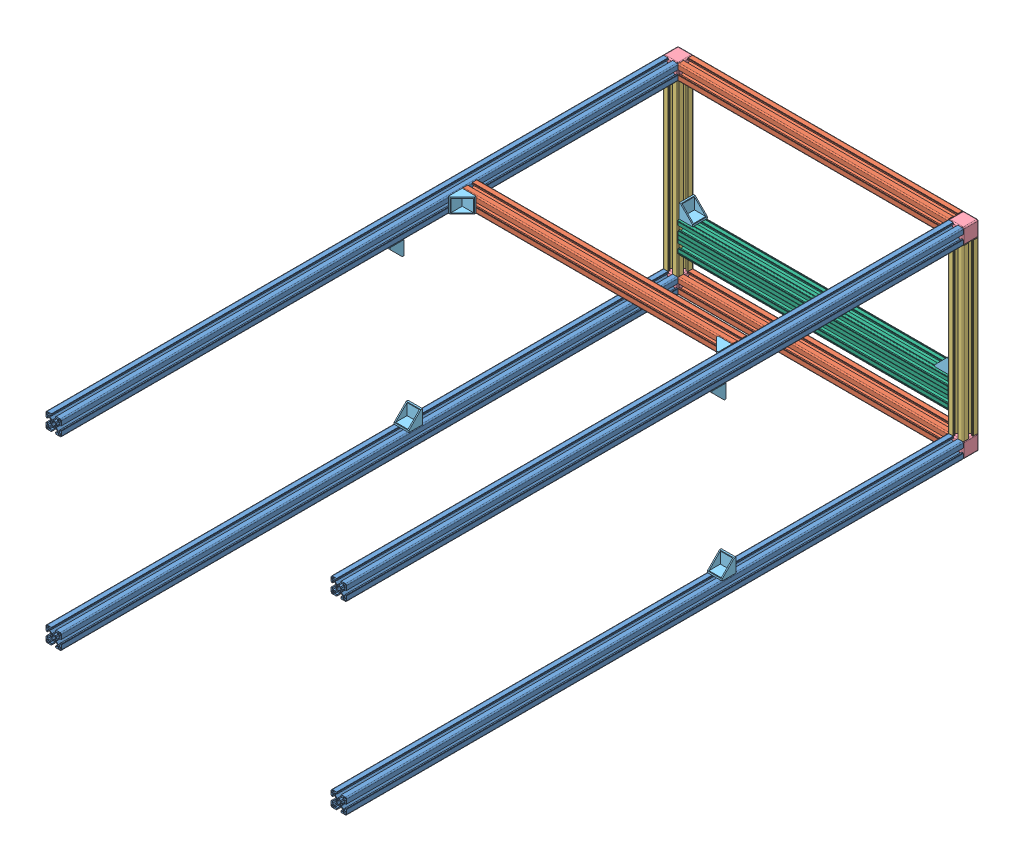
SolidWorks assembly bati partie haute, configuration Défaut. Lengths in mm.
Overall size (780 520 1640).
22 component instances, 6 part files, 59 mates.
Components (placement in the parent):
- 1636 mm-1: 1636 mm [Défaut] at (-690.2499 -110.2045 843.4804) size (40 40 1600)
- 1636 mm-2: 1636 mm [Défaut] at (49.7501 -110.2045 843.4804) x (0 1 0) z (0 0 1) size (40 40 1600)
- 1636 mm-3: 1636 mm [Défaut] at (49.7501 369.7955 843.4804) x (0 -1 0) z (0 0 1) size (40 40 1600)
- 1636 mm-4: 1636 mm [Défaut] at (-690.2499 369.7955 843.4804) size (40 40 1600)
- 700 mm-1: 700 mm [Défaut] at (-570.2499 369.7955 -676.5196) x (0 0 1) z (-1 0 0) size (40 40 700)
- 700 mm-2: 700 mm [Défaut] at (-70.2499 -110.2045 -676.5196) x (0 0 -1) z (1 0 0) size (40 40 700)
- 440 mm-1: 440 mm [Défaut] at (49.7501 249.7955 -676.5196) x (1 0 0) z (0 1 0) size (40 40 440)
- 440 mm-2: 440 mm [Défaut] at (-690.2499 249.7955 -676.5196) x (1 0 0) z (0 1 0) size (40 40 440)
- cache 40 40 40-1: cache 40 40 40 [Défaut] at (-708.8962 368.9411 -656.5196) x (-1 0 0) z (0 0 -1) size (40 40 40)
- cache 40 40 40-2: cache 40 40 40 [Défaut] at (-671.6035 -109.35 -656.5196) x (1 0 0) z (0 0 -1) size (40 40 40)
- cache 40 40 40-3: cache 40 40 40 [Défaut] at (48.8957 388.4419 -656.5196) x (0 1 0) z (0 0 -1) size (40 40 40)
- cache 40 40 40-4: cache 40 40 40 [Défaut] at (68.3965 -109.35 -656.5196) x (1 0 0) z (0 0 -1) size (40 40 40)
- 700 mm-3: 700 mm [Défaut] at (-70.2499 369.7955 -116.5196) x (0 0 -1) z (1 0 0) size (40 40 700)
- equerre 40x40-1: equerre 40x40 [Défaut] at (-670.2499 370.7955 -96.5196) x (0 1 0) z (0 0 1) size (38 36 36)
- equerre 40x40-2: equerre 40x40 [Défaut] at (-689.2499 -90.2045 6.1959) x (1 0 0) z (0 1 0) size (38 36 36)
- equerre 40x40-3: equerre 40x40 [Défaut] at (50.7501 349.7955 -40.9632) size (38 36 36)
- equerre 40x40-4: equerre 40x40 [Défaut] at (29.7501 39.7955 -677.5196) x (0 0 -1) z (-1 0 0) size (38 36 36)
- equerre 40x40-5: equerre 40x40 [Défaut] at (-689.2499 349.7955 54.8144) size (38 36 36)
- equerre 40x40-6: equerre 40x40 [Défaut] at (-670.2499 39.7955 -677.5196) x (0 0 1) z (1 0 0) size (38 36 36)
- equerre 40x40-7: equerre 40x40 [Défaut] at (29.7501 370.7955 -96.5196) x (0 -1 0) z (0 0 1) size (38 36 36)
- equerre 40x40-8: equerre 40x40 [Défaut] at (50.7501 -90.2045 -66.692) x (-1 0 0) z (0 0 1) size (38 36 36)
- 700-1: 700 [Défaut] at (-570.2499 -0.2045 -676.5196) x (0 0 1) z (-1 0 0) size (40 80 700)
Mates (geometry in assembly coordinates):
- Coïncidente5: coincident anti-aligned: plane of 1636 mm-4 through (-673.2499 352.7955 -656.5196) normal (0 0 -1); plane of cache 40 40 40-1 through (-670.2499 349.7955 -656.5196) normal (0 0 1)
- Coïncidente6: coincident aligned: plane of 1636 mm-4 through (-673.2499 389.7955 -656.5196) normal (0 1 0); plane of cache 40 40 40-1 through (-670.2499 389.7955 -696.5196) normal (0 1 0)
- Coïncidente7: coincident aligned: plane of 1636 mm-4 through (-670.2499 375.7955 -656.5196) normal (1 0 0); plane of cache 40 40 40-1 through (-670.2499 389.7955 -696.5196) normal (1 0 0)
- Coïncidente10: coincident anti-aligned: plane of 1636 mm-3 through (32.7501 352.7955 -656.5196) normal (0 0 -1); plane of cache 40 40 40-3 through (29.7501 349.7955 -656.5196) normal (0 0 1)
- Coïncidente11: coincident aligned: plane of 1636 mm-3 through (32.7501 349.7955 -656.5196) normal (0 -1 0); plane of cache 40 40 40-3 through (69.7501 349.7955 -696.5196) normal (0 -1 0)
- Coïncidente12: coincident aligned: plane of 1636 mm-3 through (69.7501 352.7955 -656.5196) normal (1 0 0); plane of cache 40 40 40-3 through (69.7501 349.7955 -696.5196) normal (1 0 0)
- Coïncidente13: coincident anti-aligned: plane of 1636 mm-2 through (66.7501 -93.2045 -656.5196) normal (0 0 -1); plane of cache 40 40 40-4 through (29.7501 -90.2045 -656.5196) normal (0 0 1)
- Coïncidente14: coincident aligned: plane of 1636 mm-2 through (32.7501 -130.2045 -656.5196) normal (0 -1 0); plane of cache 40 40 40-4 through (29.7501 -130.2045 -696.5196) normal (0 -1 0)
- Coïncidente15: coincident aligned: plane of 1636 mm-2 through (29.7501 -93.2045 -656.5196) normal (-1 0 0); plane of cache 40 40 40-4 through (29.7501 -130.2045 -696.5196) normal (-1 0 0)
- Coïncidente16: coincident aligned: plane of 1636 mm-1 through (-670.2499 -127.2045 -656.5196) normal (1 0 0); plane of cache 40 40 40-2 through (-670.2499 -130.2045 -696.5196) normal (1 0 0)
- Coïncidente17: coincident anti-aligned: plane of 1636 mm-1 through (-673.2499 -127.2045 -656.5196) normal (0 0 -1); plane of cache 40 40 40-2 through (-710.2499 -90.2045 -656.5196) normal (0 0 1)
- Coïncidente18: coincident aligned: plane of 1636 mm-1 through (-673.2499 -90.2045 -656.5196) normal (0 1 0); plane of cache 40 40 40-2 through (-710.2499 -90.2045 -696.5196) normal (0 1 0)
- Coïncidente19: coincident anti-aligned: plane of 700 mm-2 through (-670.2499 -127.2045 -693.5196) normal (-1 0 0); plane of cache 40 40 40-2 through (-670.2499 -130.2045 -696.5196) normal (1 0 0)
- Coïncidente20: coincident aligned: plane of 700 mm-2 through (-670.2499 -90.2045 -693.5196) normal (0 1 0); plane of cache 40 40 40-2 through (-710.2499 -90.2045 -696.5196) normal (0 1 0)
- Coïncidente21: coincident aligned: plane of 700 mm-2 through (-670.2499 -127.2045 -696.5196) normal (0 0 -1); plane of cache 40 40 40-2 through (-710.2499 -90.2045 -696.5196) normal (0 0 -1)
- Coïncidente22: coincident anti-aligned: plane of 700 mm-2 through (29.7501 -127.2045 -693.5196) normal (1 0 0); plane of cache 40 40 40-4 through (29.7501 -130.2045 -696.5196) normal (-1 0 0)
- Coïncidente23: coincident aligned: plane of 700 mm-2 through (-670.2499 -127.2045 -696.5196) normal (0 0 -1); plane of cache 40 40 40-4 through (29.7501 -90.2045 -696.5196) normal (0 0 -1)
- Coïncidente24: coincident aligned: plane of 700 mm-2 through (-670.2499 -90.2045 -693.5196) normal (0 1 0); plane of cache 40 40 40-4 through (29.7501 -90.2045 -696.5196) normal (0 1 0)
- Coïncidente25: coincident anti-aligned: plane of 440 mm-1 through (66.7501 -90.2045 -659.5196) normal (0 -1 0); plane of cache 40 40 40-4 through (29.7501 -90.2045 -696.5196) normal (0 1 0)
- Coïncidente26: coincident aligned: plane of 440 mm-1 through (69.7501 -90.2045 -659.5196) normal (1 0 0); plane of cache 40 40 40-4 through (69.7501 -130.2045 -696.5196) normal (1 0 0)
- Coïncidente27: coincident aligned: plane of 440 mm-1 through (66.7501 -90.2045 -696.5196) normal (0 0 -1); plane of cache 40 40 40-4 through (29.7501 -90.2045 -696.5196) normal (0 0 -1)
- Coïncidente28: coincident anti-aligned: plane of 440 mm-1 through (66.7501 349.7955 -659.5196) normal (0 1 0); plane of cache 40 40 40-3 through (69.7501 349.7955 -696.5196) normal (0 -1 0)
- Coïncidente29: coincident aligned: plane of 440 mm-1 through (69.7501 -90.2045 -659.5196) normal (1 0 0); plane of cache 40 40 40-3 through (69.7501 349.7955 -696.5196) normal (1 0 0)
- Coïncidente30: coincident aligned: plane of 440 mm-1 through (43.7501 -90.2045 -696.5196) normal (0 0 -1); plane of cache 40 40 40-3 through (29.7501 349.7955 -696.5196) normal (0 0 -1)
- Coïncidente31: coincident anti-aligned: plane of 700 mm-1 through (29.7501 352.7955 -659.5196) normal (1 0 0); plane of cache 40 40 40-3 through (29.7501 349.7955 -696.5196) normal (-1 0 0)
- Coïncidente32: coincident aligned: plane of 700 mm-1 through (29.7501 389.7955 -682.5196) normal (0 1 0); plane of cache 40 40 40-3 through (69.7501 389.7955 -696.5196) normal (0 1 0)
- Coïncidente33: coincident aligned: plane of 700 mm-1 through (29.7501 363.7955 -696.5196) normal (0 0 -1); plane of cache 40 40 40-3 through (29.7501 349.7955 -696.5196) normal (0 0 -1)
- Coïncidente34: coincident anti-aligned: plane of 700 mm-1 through (-670.2499 352.7955 -659.5196) normal (-1 0 0); plane of cache 40 40 40-1 through (-670.2499 389.7955 -696.5196) normal (1 0 0)
- Coïncidente35: coincident aligned: plane of 700 mm-1 through (29.7501 389.7955 -682.5196) normal (0 1 0); plane of cache 40 40 40-1 through (-670.2499 389.7955 -696.5196) normal (0 1 0)
- Coïncidente36: coincident aligned: plane of 700 mm-1 through (29.7501 363.7955 -696.5196) normal (0 0 -1); plane of cache 40 40 40-1 through (-670.2499 349.7955 -696.5196) normal (0 0 -1)
- Coïncidente37: coincident anti-aligned: plane of 440 mm-2 through (-673.2499 -90.2045 -659.5196) normal (0 -1 0); plane of cache 40 40 40-2 through (-710.2499 -90.2045 -696.5196) normal (0 1 0)
- Coïncidente38: coincident aligned: plane of 440 mm-2 through (-696.2499 -90.2045 -696.5196) normal (0 0 -1); plane of cache 40 40 40-2 through (-710.2499 -90.2045 -696.5196) normal (0 0 -1)
- Coïncidente39: coincident aligned: plane of 440 mm-2 through (-710.2499 -90.2045 -693.5196) normal (-1 0 0); plane of cache 40 40 40-2 through (-710.2499 -130.2045 -696.5196) normal (-1 0 0)
- Coïncidente49: coincident anti-aligned: plane of 1636 mm-4 through (-670.2499 352.7955 -656.5196) normal (1 0 0); plane of 700 mm-3 through (-670.2499 352.7955 -133.5196) normal (-1 0 0)
- Coïncidente50: coincident aligned: plane of 1636 mm-4 through (-673.2499 389.7955 -656.5196) normal (0 1 0); plane of 700 mm-3 through (-670.2499 389.7955 -110.5196) normal (0 1 0)
- Distance6: distance = 520 mm anti-aligned: plane of 700 mm-3 through (-670.2499 375.7955 -136.5196) normal (0 0 -1); plane of 700 mm-1 through (29.7501 375.7955 -656.5196) normal (0 0 1)
- Coïncidente55: coincident anti-aligned: plane of 1636 mm-4 through (-670.2499 352.7955 -656.5196) normal (1 0 0); plane of equerre 40x40-1 through (-670.2499 351.7955 -96.5196) normal (-1 0 0)
- Coïncidente56: coincident aligned: plane of 1636 mm-4 through (-673.2499 389.7955 -656.5196) normal (0 1 0); plane of equerre 40x40-1 through (-634.2499 389.7955 -96.5196) normal (0 1 0)
- Coïncidente57: coincident anti-aligned: plane of 700 mm-3 through (-670.2499 386.7955 -96.5196) normal (0 0 1); plane of equerre 40x40-1 through (-634.2499 351.7955 -96.5196) normal (0 0 -1)
- Coïncidente58: coincident anti-aligned: plane of 1636 mm-4 through (-684.2499 349.7955 -656.5196) normal (0 -1 0); plane of equerre 40x40-5 through (-708.2499 349.7955 54.8144) normal (0 1 0)
- Coïncidente59: coincident aligned: plane of 1636 mm-4 through (-670.2499 352.7955 -656.5196) normal (1 0 0); plane of equerre 40x40-5 through (-670.2499 313.7955 54.8144) normal (1 0 0)
- Coïncidente61: coincident aligned: plane of 1636 mm-1 through (-670.2499 -104.2045 -656.5196) normal (1 0 0); plane of equerre 40x40-2 through (-670.2499 -90.2045 42.1959) normal (1 0 0)
- Coïncidente63: coincident anti-aligned: plane of 1636 mm-1 through (-696.2499 -90.2045 -656.5196) normal (0 1 0); plane of equerre 40x40-2 through (-708.2499 -90.2045 42.1959) normal (0 -1 0)
- Coïncidente64: coincident anti-aligned: plane of 1636 mm-3 through (55.7501 349.7955 -656.5196) normal (0 -1 0); plane of equerre 40x40-3 through (31.7501 349.7955 -40.9632) normal (0 1 0)
- Coïncidente65: coincident aligned: plane of 1636 mm-3 through (69.7501 352.7955 -656.5196) normal (1 0 0); plane of equerre 40x40-3 through (69.7501 313.7955 -40.9632) normal (1 0 0)
- Coïncidente67: coincident anti-aligned: plane of 1636 mm-2 through (66.7501 -90.2045 -656.5196) normal (0 1 0); plane of equerre 40x40-8 through (69.7501 -90.2045 -66.692) normal (0 -1 0)
- Coïncidente68: coincident aligned: plane of 1636 mm-2 through (69.7501 -127.2045 -656.5196) normal (1 0 0); plane of equerre 40x40-8 through (69.7501 -54.2045 -66.692) normal (1 0 0)
- Coïncidente70: coincident anti-aligned: plane of 1636 mm-3 through (29.7501 386.7955 -656.5196) normal (-1 0 0); plane of equerre 40x40-7 through (29.7501 389.7955 -96.5196) normal (1 0 0)
- Coïncidente71: coincident aligned: plane of 1636 mm-3 through (43.7501 389.7955 -656.5196) normal (0 1 0); plane of equerre 40x40-7 through (-6.2499 389.7955 -96.5196) normal (0 1 0)
- Coïncidente72: coincident anti-aligned: plane of 700 mm-3 through (-670.2499 386.7955 -96.5196) normal (0 0 1); plane of equerre 40x40-7 through (-6.2499 389.7955 -96.5196) normal (0 0 -1)
- Coïncidente79: coincident anti-aligned: plane of 440 mm-1 through (29.7501 -90.2045 -693.5196) normal (-1 0 0); plane of 700-1 through (29.7501 19.7955 -676.5196) normal (1 0 0)
- Coïncidente80: coincident aligned: plane of 440 mm-1 through (43.7501 -90.2045 -696.5196) normal (0 0 -1); plane of 700-1 through (29.7501 13.7955 -696.5196) normal (0 0 -1)
- Distance8: distance = 130 mm anti-aligned: plane of 440 mm-1 through (66.7501 -90.2045 -659.5196) normal (0 -1 0); plane of 700-1 through (29.7501 39.7955 -682.5196) normal (0 1 0)
- Coïncidente83: coincident anti-aligned: plane of equerre 40x40-6 through (-670.2499 39.7955 -696.5196) normal (0 -1 0); plane of 700-1 through (29.7501 39.7955 -682.5196) normal (0 1 0)
- Coïncidente84: coincident anti-aligned: plane of 440 mm-2 through (-670.2499 -90.2045 -682.5196) normal (1 0 0); plane of equerre 40x40-6 through (-670.2499 75.7955 -696.5196) normal (-1 0 0)
- Coïncidente85: coincident aligned: plane of equerre 40x40-6 through (-670.2499 75.7955 -696.5196) normal (0 0 -1); plane of 700-1 through (29.7501 34.2955 -696.5196) normal (0 0 -1)
- Coïncidente86: coincident anti-aligned: plane of equerre 40x40-4 through (29.7501 39.7955 -658.5196) normal (0 -1 0); plane of 700-1 through (29.7501 39.7955 -682.5196) normal (0 1 0)
- Coïncidente87: coincident anti-aligned: plane of 440 mm-1 through (29.7501 -90.2045 -693.5196) normal (-1 0 0); plane of equerre 40x40-4 through (29.7501 75.7955 -658.5196) normal (1 0 0)
- Coïncidente88: coincident aligned: plane of equerre 40x40-4 through (29.7501 75.7955 -696.5196) normal (0 0 -1); plane of 700-1 through (29.7501 34.2955 -696.5196) normal (0 0 -1)
